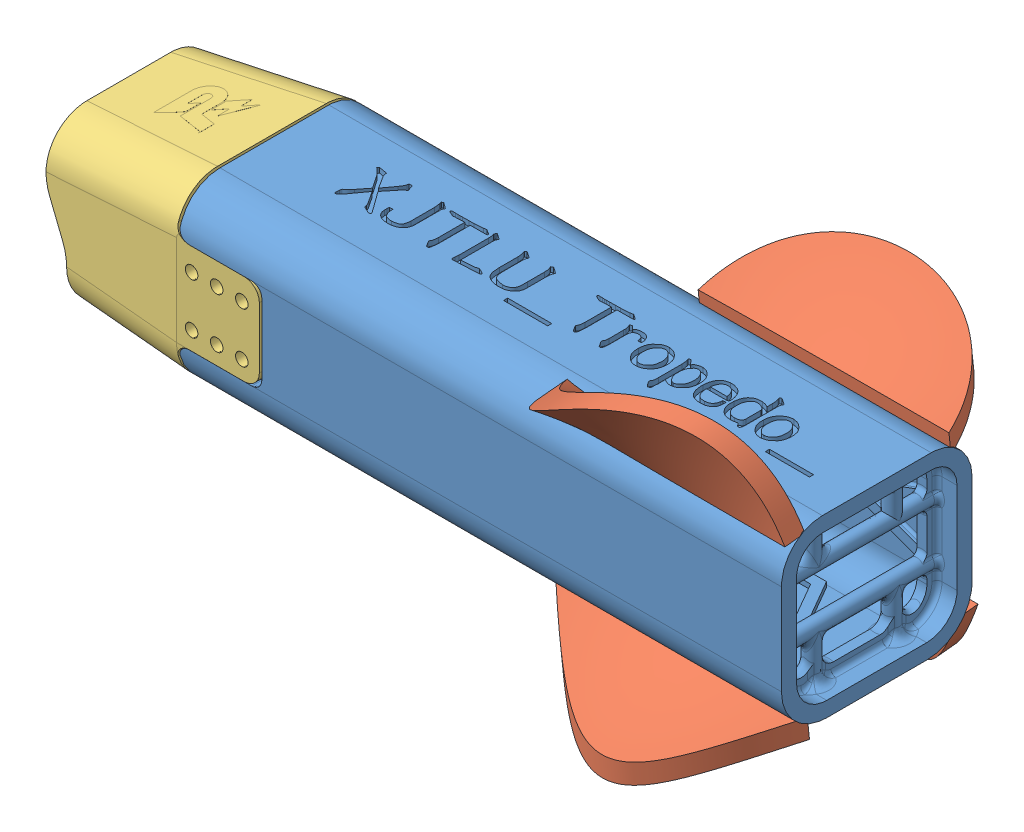
SolidWorks assembly 飞镖, configuration 默认. Lengths in mm.
Overall size (151.84 75.91 75.36).
6 component instances, 3 part files, 15 mates.
Components (placement in the parent):
- Tropedo_Body_V1-1: Tropedo_Body_V1 [默认] at (-106.8542 4.5498 -0.0001) size (120 35.32 38.22)
- 17右上螺旋翼-1: 17右上螺旋翼 [默认] at (-26.8542 38.1319 18.8007) x (0 0.104528 -0.994522) z (1 0 0) size (25.84 27.26 62.83)
- 17右上螺旋翼-2: 17右上螺旋翼 [默认] at (-26.8542 9.1481 -20.6645) x (0 -0.104528 0.994522) z (1 0 0) size (25.84 27.26 62.83)
- 17右上螺旋翼-3: 17右上螺旋翼 [默认] at (-26.8542 2.0359 13.35) x (0 0.994522 0.104528) z (1 0 0) size (25.84 27.26 62.83)
- 17右上螺旋翼-4: 17右上螺旋翼 [默认] at (-26.8542 42.0551 -14.3247) x (0 -0.994522 -0.104528) z (1 0 0) size (25.84 27.26 62.83)
- 21RM-机械飞镖-官方出发装置-1: 21RM-机械飞镖-官方出发装置 [默认] at (-175.7078 4.6999 -0.0158) x (0 0 1) z (-1 0 0) size (38.01 35.32 45.01)
Mates (geometry in assembly coordinates):
- 重合11: coincident aligned: plane of Tropedo_Body_V1-1 through (-26.8542 13.5535 9.9594) normal (1 0 0); plane of 17右上螺旋翼-1 through (-26.8542 38.1319 18.8007) normal (1 0 0)
- 重合4: coincident aligned: plane of 17右上螺旋翼-1 through (-26.8542 38.1319 18.8007) normal (1 0 0); plane of 17右上螺旋翼-3 through (-26.8542 2.0359 13.35) normal (1 0 0)
- 重合6: coincident aligned: plane of 17右上螺旋翼-2 through (-26.8542 9.1481 -20.6645) normal (1 0 0); plane of 17右上螺旋翼-3 through (-26.8542 2.0359 13.35) normal (1 0 0)
- 重合8: coincident aligned: plane of 17右上螺旋翼-1 through (-26.8542 38.1319 18.8007) normal (1 0 0); plane of 17右上螺旋翼-4 through (-26.8542 42.0551 -14.3247) normal (1 0 0)
- 相切1: tangent: curve of Tropedo_Body_V1-1; plane of 17右上螺旋翼-3 through (-26.8542 5.9769 10.1586) normal (0 0.777146 -0.62932)
- 相切3: tangent: curve of Tropedo_Body_V1-1; plane of 17右上螺旋翼-2 through (-26.8542 12.3395 -16.7236) normal (0 0.62932 0.777146)
- 相切4: tangent: curve of Tropedo_Body_V1-1; plane of 17右上螺旋翼-4 through (-26.8542 38.1141 -11.1333) normal (0 -0.777146 0.62932)
- 相切5: tangent: curve of Tropedo_Body_V1-1; plane of 17右上螺旋翼-1 through (-26.8542 34.9406 14.8597) normal (0 -0.62932 -0.777146)
- 平行6: parallel anti-aligned: line of Tropedo_Body_V1-1 through (-26.8542 7.2098 14.9999) axis (0 0.707107 -0.707107); line of 17右上螺旋翼-3 through (-76.8542 7.9794 12.6315) axis (0 -0.707107 0.707107)
- 平行7: parallel aligned: line of Tropedo_Body_V1-1 through (-26.8542 37.2098 14.9999) axis (0 -0.707107 -0.707107); line of 17右上螺旋翼-2 through (-76.8542 9.8666 -14.7211) axis (0 -0.707107 -0.707107)
- 平行8: parallel aligned: line of Tropedo_Body_V1-1 through (-26.8542 7.2098 14.9999) axis (0 0.707107 -0.707107); line of 17右上螺旋翼-4 through (-76.8542 36.1116 -13.6062) axis (0 0.707107 -0.707107)
- 平行9: parallel anti-aligned: line of Tropedo_Body_V1-1 through (-26.8542 37.2098 14.9999) axis (0 -0.707107 -0.707107); line of 17右上螺旋翼-1 through (-76.8542 37.4134 12.8573) axis (0 0.707107 0.707107)
- 同心2: concentric: cylinder of Tropedo_Body_V1-1 through (-134.3542 27.169 -18.9945) axis (0 0 1) radius 1.25; cylinder of 21RM-机械飞镖-官方出发装置-1 through (-134.3542 27.169 18.9862) axis (0 0 1) radius 1.25
- 同心3: concentric: cylinder of Tropedo_Body_V1-1 through (-134.3542 27.169 -18.9945) axis (0 0 1) radius 1.25; cylinder of 21RM-机械飞镖-官方出发装置-1 through (-134.3542 27.169 -19.0016) axis (0 0 -1) radius 1.25
- 重合15: coincident anti-aligned: plane of Tropedo_Body_V1-1 through (-106.8542 4.5498 -16.994) normal (0 0 -1); plane of 21RM-机械飞镖-官方出发装置-1 through (-147.3542 31.669 -16.994) normal (0 0 1)
